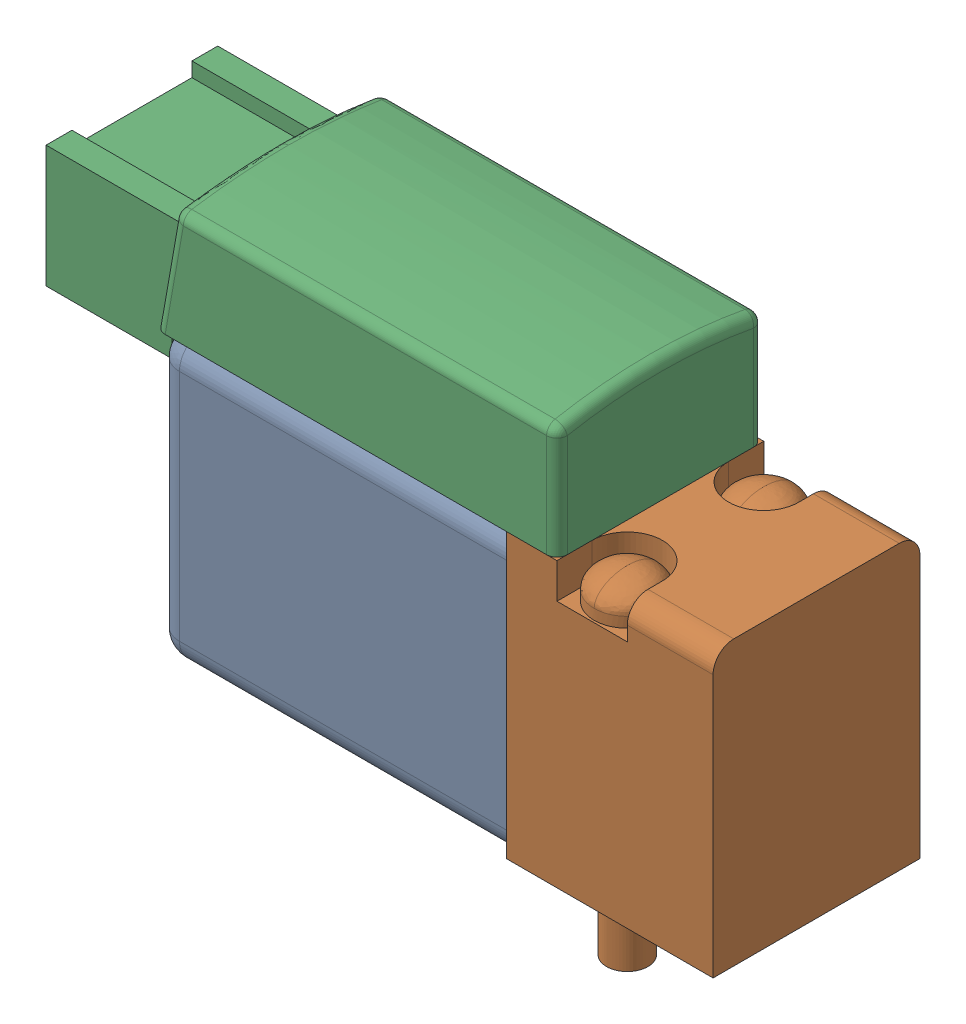
SolidWorks assembly SYJ3120-SMO-M3-F.step_V100_V111-SMO, configuration Default. Lengths in mm.
Overall size (33.1 22.4 10).
2 component instances, 2 part files, 0 mates.
Components (placement in the parent):
- SYJ3120-SMO-M3-F.step_V100_1-1: SYJ3120-SMO-M3-F.step_V100_1 [Default] at origin size (27 16.5 10)
- SYJ3120-SMO-M3-F.step_V100 Cover_M-1: SYJ3120-SMO-M3-F.step_V100 Cover_M [Default] at (-7.55 13.7 0) size (25.55 7.6 10)
